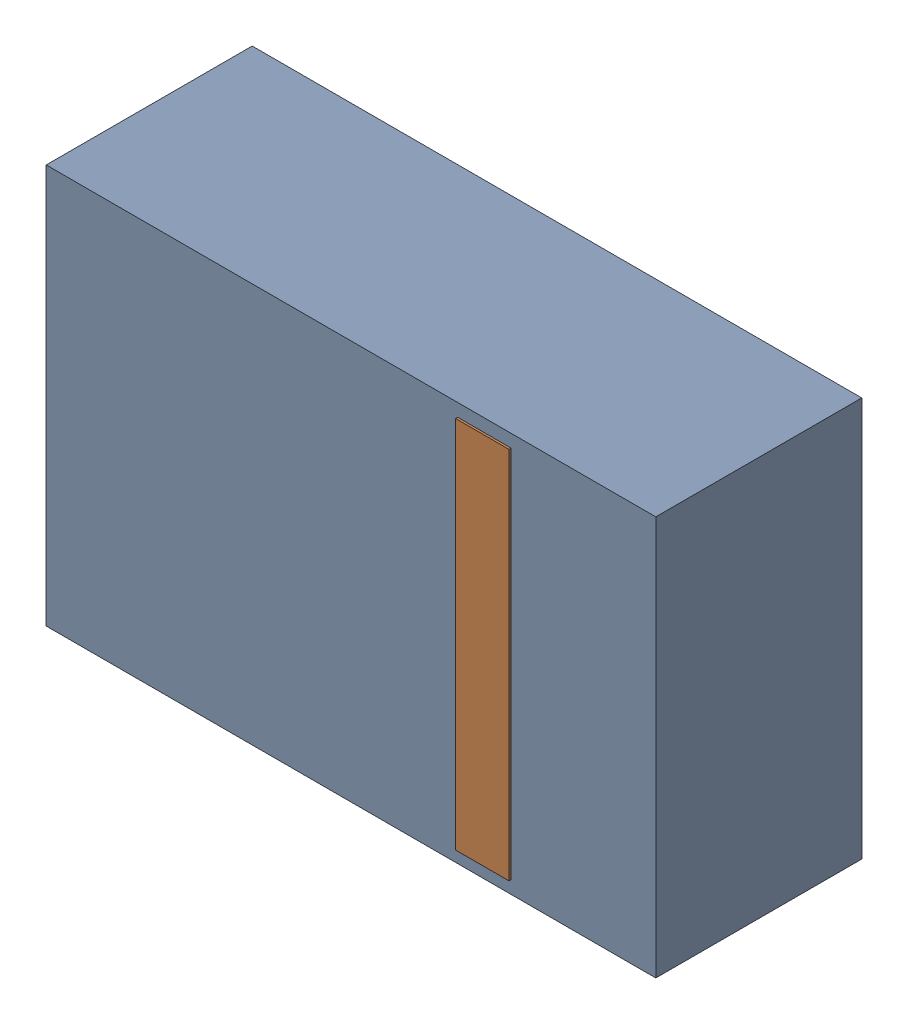
SolidWorks assembly D10, configuration Default. Lengths in mm.
Overall size (2.9 1.9 0.99).
4 component instances, 2 part files, 0 mates.
Components (placement in the parent):
- 905269392-1: 905269392 [Default] at (92.075 72.898 0) size (2.9 1.9 0.98)
  - Extruded_5-1: Extruded_5 [Default] at origin size (2.9 1.9 0.98)
- 905269800-1: 905269800 [Default] at (92.71 72.898 0.95) size (0.25 1.78 0.04)
  - Extruded_6-1: Extruded_6 [Default] at origin size (0.25 1.78 0.04)
